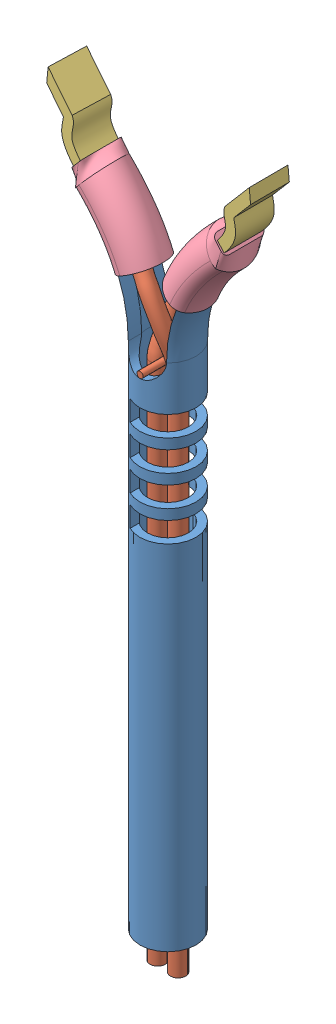
SolidWorks assembly ham1, configuration Default. Lengths in mm.
Overall size (9.74 28.87 2.56).
6 component instances, 4 part files, 5 mates.
Components (placement in the parent):
- tube-1: tube [Default] at origin size (6.18 24.36 2.2)
- Part2-2: Part2 [Default] at origin size (4.16 25.27 2.56)
- tip_small_v2-2: tip_small_v2 [Default] at (-3.0258 26.4462 -0.7804) x (0.759045 0.650985 -0.008349) z (-0.008349 0.022556 0.999711) size (1.13 4.43 1.5)
- tip_small_v2-3: tip_small_v2 [Default] at (3.0225 26.4492 0.7755) x (-0.758982 0.651107 0.002397) z (0.012867 0.01868 -0.999743) size (1.13 4.43 1.5)
- heat_shrink-1: heat_shrink [Default] at origin size (2.89 3.47 1.93)
- heat_shrink-3: heat_shrink [Default] at (0 0 0.0001) x (-1 0 0) z (0 0 -1) size (2.89 3.47 1.93)
Mates (geometry in assembly coordinates):
- Coincident1: coordinate: point of ?
- Coincident4: coincident anti-aligned: plane of Part2-2 through (-1.8325 23.8084 0.0393) normal (-0.650985 0.758756 -0.022556); plane of tip_small_v2-2 through (-1.8325 23.8084 0.0393) normal (0.650985 -0.758756 0.022556)
- Coincident5: coincident aligned: circle of Part2-2; circle of tip_small_v2-2
- Coincident7: coincident anti-aligned: plane of Part2-2 through (1.8325 23.8084 -0.0393) normal (0.650985 0.758756 0.022556); plane of tip_small_v2-3 through (1.8325 23.8084 -0.0393) normal (-0.650985 -0.758756 -0.022556)
- Coincident8: coincident aligned: circle of Part2-2; circle of tip_small_v2-3
